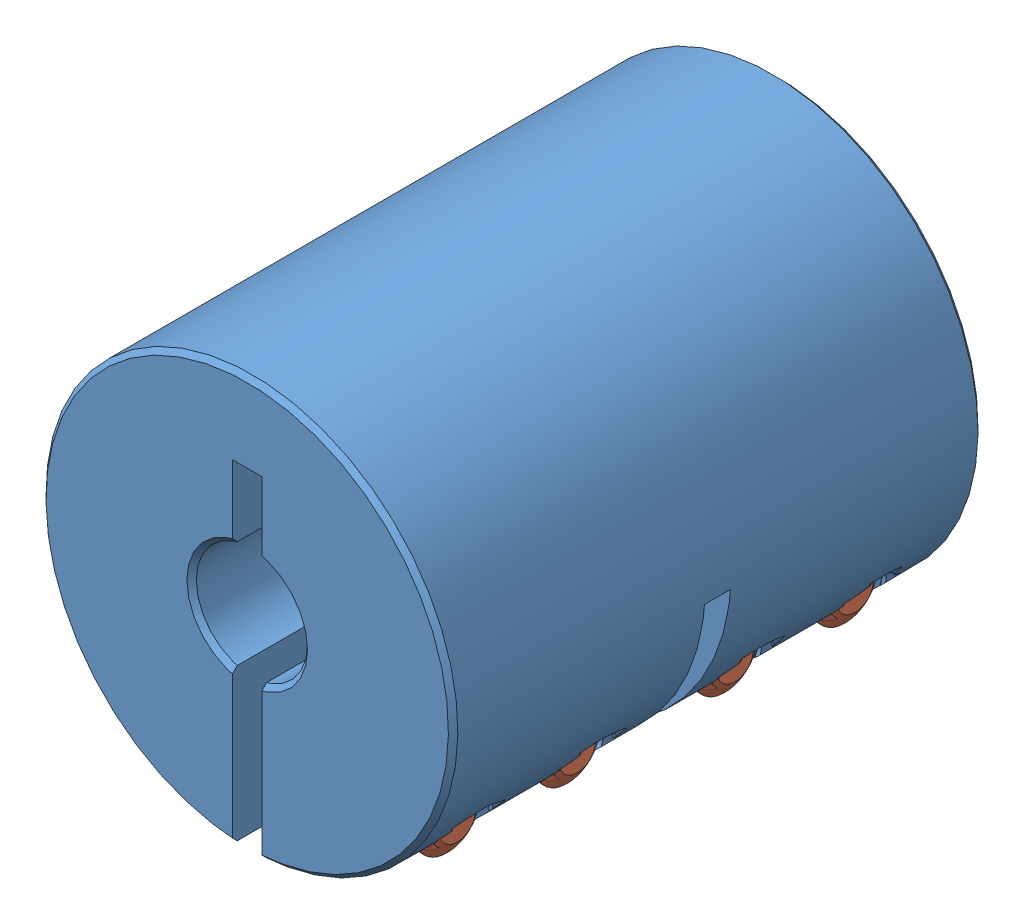
SolidWorks assembly 0.25 to 6mm Clamping Coupler, configuration Default. Lengths in mm.
Overall size (22.23 22.2 28.58).
5 component instances, 2 part files, 0 mates.
Components (placement in the parent):
- 625100-1: 625100 [Default] at (-36.0907 -0.3474 4.9835) size (22.23 22.2 28.58)
- 632112_90128A121-1: 632112_90128A121 [Default] at (-1.3244 -7.8756 30.0025) x (0 0 -1) z (1 0 0) size (5.6 5.6 14.62)
- 632112_90128A121-2: 632112_90128A121 [Default] at (-1.3244 -7.8756 23.5255) x (0 0 -1) z (1 0 0) size (5.6 5.6 14.62)
- 632112_90128A121-3: 632112_90128A121 [Default] at (-1.3244 -7.8756 15.0165) x (0 0 -1) z (1 0 0) size (5.6 5.6 14.62)
- 632112_90128A121-4: 632112_90128A121 [Default] at (-1.3244 -7.8756 8.5395) x (0 0 -1) z (1 0 0) size (5.6 5.6 14.62)
